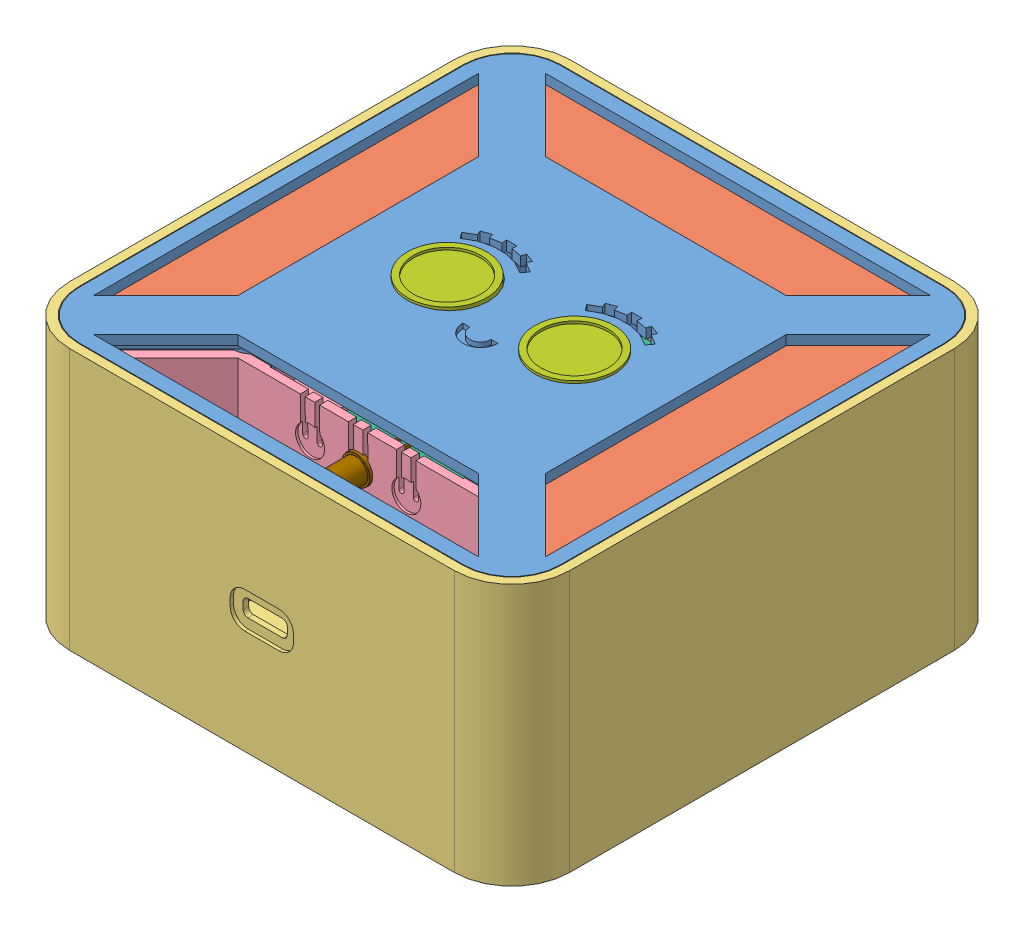
SolidWorks assembly SensorAparcacoches, configuration Default. Lengths in mm.
Overall size (104 54.84 104).
15 component instances, 10 part files, 44 mates.
Components (placement in the parent):
- PlacaFrontal-1: PlacaFrontal [Default] at (-104.2944 -40.3646 79.7073) size (100 19 100)
- Difusor-1: Difusor [Default] at (-104.2944 -40.3646 79.7073) x (-1 0 0) z (0 -1 0) size (84 19 1)
- Difusor-2: Difusor [Default] at (-104.2944 -41.3646 -20.2927) x (-1 0 0) z (0 1 0) size (84 19 1) (hidden)
- Difusor-3: Difusor [Default] at (-104.2944 -41.3646 79.7073) x (0 0 1) z (0 1 0) size (84 19 1)
- Difusor-4: Difusor [Default] at (-4.2944 -41.3646 -20.2927) x (0 0 -1) z (0 1 0) size (84 19 1)
- Cuerpo-2: Cuerpo [Default] at (-4.2944 -54.7045 -20.2927) x (1 0 0) z (0 -1 0) size (104 104 54.34)
- CuadroCentral-1: CuadroCentral [Default] at (-104.2944 -57.3646 79.7073) x (-1 0 0) z (0 -1 0) size (97.8 97.8 18.8)
- Separador-1: Separador [Default] at (-104.2944 -61.3646 79.7073) x (-1 0 0) z (0 -1 0) size (7.47 7.39 15)
- PCB-1: PCB [Default] at (-104.2944 -57.3646 59.978) x (-1 0 0) z (0 0 -1) size (40.2 1.73 60)
- Separador-2: Separador [Default] at (65.7331 -61.3646 -20.2883) x (1 0 0) z (0 -1 0) size (7.47 7.39 15)
- Separador-3: Separador [Default] at (-4.4768 -61.3646 -20.3368) x (1 0 0) z (0 -1 0) size (7.47 7.39 15)
- Ultrassonic sensor HC-SR04-1: Ultrassonic sensor HC-SR04 [Valor predeterminado] at (-77.0515 -50.8646 39.6819) x (1 0 0.000711) z (0 1 0) size (45 23.45 17)
- Arduino-UNO-1: Arduino-UNO [Default] at (-63.9444 -86.5045 52.2561) x (0 0 1) z (-1 0 0) size (53.5 14.9 75.11)
- LED D5 - Red-1: LED D5 - Red [Default] at (-54.2349 -49.9643 61.2596) x (0.98812 0.153685 0) z (0 0 1) size (5.54 5.91 35)
- Altavoz-1: Altavoz [Predeterminado] at (-52.8229 -58.4343 12.7922) size (11.85 15.9 11.85)
Mates (geometry in assembly coordinates):
- InPlace1: in place: plane of ? through (-47.3914 4.3714 47.3521) normal (0 -1 0); plane of ? through (0 4.3714 0) normal (0 -1 0); moOrthogonalPlaneRef_w of ? through (-47.3914 4.3714 47.3521) normal (0 -1 0); plane of ? through (0 4.3714 0) normal (0 0 -1); plane of ? through (-47.3914 4.3714 47.3521) normal (0 -1 0); plane of ? through (0 4.3714 0) normal (-1 0 0); plane of PlacaFrontal-1 through (-104.2944 -40.3646 79.7073) normal (0 -1 0); unknown of ?
- Coincident1: coincident aligned: plane of PlacaFrontal-1; plane of ?
- Coincident2: coincident aligned: moOrthogonalPlaneRef_w of PlacaFrontal-1 through (-104.2944 -40.3646 79.7073) normal (0 0 -1); plane of Part2^SensorAparcacoches-1 through (-47.3914 4.3714 47.3521) normal (0 0 -1)
- Coincident3: coincident anti-aligned: moOrthogonalPlaneRef_w of PlacaFrontal-1 through (-104.2944 -40.3646 79.7073) normal (1 0 0); plane of Part2^SensorAparcacoches-1 through (-47.3914 4.3714 47.3521) normal (-1 0 0)
- InPlace2: in place: plane of ? through (-47.3914 4.3714 47.3521) normal (0 -1 0); plane of ? through (0 4.3714 0) normal (0 -1 0); plane of ? through (-47.3914 4.3714 47.3521) normal (0 -1 0); plane of ? through (0 4.3714 0) normal (0 0 -1); plane of ? through (-47.3914 4.3714 47.3521) normal (0 -1 0); plane of ? through (0 4.3714 0) normal (-1 0 0); plane of PlacaFrontal-1 through (-104.2944 -40.3646 79.7073) normal (0 -1 0); unknown of Difusor-1
- Coincident5: coincident aligned: plane of PlacaFrontal-1; plane of Difusor-1
- Coincident6: coincident aligned: moOrthogonalPlaneRef_w of PlacaFrontal-1 through (-104.2944 -40.3646 79.7073) normal (0 0 -1); plane of Difusor-1 through (-104.2944 -40.3646 79.7073) normal (0 0 -1)
- Coincident7: coincident anti-aligned: moOrthogonalPlaneRef_w of PlacaFrontal-1 through (-104.2944 -40.3646 79.7073) normal (1 0 0); plane of Difusor-1 through (-104.2944 -40.3646 79.7073) normal (-1 0 0)
- Coincident8: coincident anti-aligned: plane of PlacaFrontal-1 through (-104.2944 -40.3646 79.7073) normal (0 -1 0); plane of Difusor-4 through (-101.2944 -40.3646 -10.2927) normal (0 1 0)
- Coincident9: coincident anti-aligned: plane of PlacaFrontal-1 through (-84.2944 -42.3646 79.7073) normal (-1 0 0); plane of Difusor-4 through (-84.2944 -40.3646 54.3476) normal (1 0 0)
- Coincident10: coincident anti-aligned: plane of PlacaFrontal-1 through (-56.3802 -42.3646 31.7931) normal (-0.707107 0 0.707107); plane of Difusor-4 through (-85.2452 -40.3646 2.9281) normal (0.707107 0 -0.707107)
- Coincident11: coincident anti-aligned: plane of PlacaFrontal-1 through (-24.2944 -42.3646 79.7073) normal (1 0 0); plane of Difusor-3 through (-24.2944 -40.3646 5.067) normal (-1 0 0)
- Coincident12: coincident anti-aligned: plane of PlacaFrontal-1 through (-104.2944 -40.3646 79.7073) normal (0 -1 0); plane of Difusor-3 through (-7.2944 -40.3646 69.7073) normal (0 1 0)
- Coincident13: coincident anti-aligned: plane of PlacaFrontal-1 through (-52.2086 -42.3646 27.6215) normal (0.707107 0 -0.707107); plane of Difusor-3 through (-23.3436 -40.3646 56.4865) normal (-0.707107 0 0.707107)
- Coincident14: coincident anti-aligned: plane of PlacaFrontal-1 through (-104.2944 -40.3646 79.7073) normal (0 -1 0); plane of Difusor-2 through (-94.2944 -40.3646 76.7073) normal (0 1 0)
- Coincident15: coincident anti-aligned: plane of PlacaFrontal-1 through (-104.2944 -42.3646 59.7073) normal (0 0 1); plane of Difusor-2 through (-29.6541 -40.3646 59.7073) normal (0 0 -1)
- Coincident16: coincident anti-aligned: plane of PlacaFrontal-1 through (-56.3802 -42.3646 31.7931) normal (-0.707107 0 0.707107); plane of Difusor-2 through (-12.8802 -40.3646 75.2931) normal (0.707107 0 -0.707107)
- Coincident19: coincident anti-aligned: plane of arduino-1 through (-64.9444 -86.5045 52.1061) normal (0 -1 0); plane of Cuerpo-2 through (-96.9444 -86.5045 60.4073) normal (0 1 0)
- Concentric1: concentric anti-aligned: cylinder of arduino-1 through (-46.4444 -86.5045 27.6061) axis (0 1 0) radius 1.5; cylinder of Cuerpo-2 through (-44.9444 -86.5045 28.0061) axis (0 -1 0) radius 1.5
- Parallel1: parallel aligned: plane of arduino-1 through (-97.4444 -85.0045 78.6061) normal (0 0 1); plane of Cuerpo-2 through (-4.2944 108.7136 81.7073) normal (0 0 1)
- Parallel2: parallel anti-aligned: plane of PlacaFrontal-1 through (-104.2944 -40.3646 79.7073) normal (0 -1 0); plane of Cuerpo-2 through (-14.2944 -89.7045 -10.2927) normal (0 1 0)
- Concentric2: concentric aligned: cylinder of PlacaFrontal-1 through (-14.2944 -38.3646 -10.2927) axis (0 -1 0) radius 10; cylinder of Cuerpo-2 through (-14.2944 108.7136 -10.2927) axis (0 -1 0) radius 10.15
- Concentric3: concentric aligned: cylinder of PlacaFrontal-1 through (-94.2944 -38.3646 69.7073) axis (0 -1 0) radius 10; cylinder of Cuerpo-2 through (-94.2944 108.7136 69.7073) axis (0 -1 0) radius 10.15
- InPlace3: in place: plane of PlacaFrontal-1 through (-81.2944 -57.3646 56.7073) normal (0 -1 0); plane of ? through (0 -57.3646 0) normal (0 -1 0); plane of PlacaFrontal-1 through (-81.2944 -57.3646 56.7073) normal (0 -1 0); plane of ? through (0 -57.3646 0) normal (0 0 -1); plane of PlacaFrontal-1 through (-81.2944 -57.3646 56.7073) normal (0 -1 0); plane of ? through (0 -57.3646 0) normal (-1 0 0); plane of PlacaFrontal-1 through (-81.2944 -57.3646 56.7073) normal (0 -1 0); unknown of CuadroCentral-1
- Coincident23: coincident aligned: plane of PlacaFrontal-1; plane of CuadroCentral-1
- Coincident24: coincident aligned: moOrthogonalPlaneRef_w of PlacaFrontal-1 through (-104.2944 -57.3646 79.7073) normal (0 0 -1); plane of CuadroCentral-1 through (-104.2944 -57.3646 79.7073) normal (0 0 -1)
- Coincident25: coincident anti-aligned: moOrthogonalPlaneRef_w of PlacaFrontal-1 through (-104.2944 -57.3646 79.7073) normal (1 0 0); plane of CuadroCentral-1 through (-104.2944 -57.3646 79.7073) normal (-1 0 0)
- InPlace4: in place: plane of CuadroCentral-1 through (-104.2944 -61.3646 79.7073) normal (0 -1 0); plane of ? through (0 -61.3646 0) normal (0 -1 0); plane of CuadroCentral-1 through (-104.2944 -61.3646 79.7073) normal (0 -1 0); plane of ? through (0 -61.3646 0) normal (0 0 -1); plane of CuadroCentral-1 through (-104.2944 -61.3646 79.7073) normal (0 -1 0); plane of ? through (0 -61.3646 0) normal (-1 0 0); plane of CuadroCentral-1 through (-104.2944 -61.3646 79.7073) normal (0 -1 0); unknown of Separador-1
- Coincident20: coincident aligned: plane of CuadroCentral-1; plane of Separador-1
- Coincident21: coincident aligned: moOrthogonalPlaneRef_w of CuadroCentral-1 through (-104.2944 -61.3646 79.7073) normal (0 0 -1); plane of Part5^SensorAparcacoches-1 through (-104.2944 -61.3646 79.7073) normal (0 0 -1)
- Coincident22: coincident anti-aligned: moOrthogonalPlaneRef_w of CuadroCentral-1 through (-104.2944 -61.3646 79.7073) normal (1 0 0); plane of Part5^SensorAparcacoches-1 through (-104.2944 -61.3646 79.7073) normal (-1 0 0)
- InPlace5: in place: plane of CuadroCentral-1 through (-104.2944 -35.5646 59.878) normal (0 0 -1); plane of ? through (0 0 59.878) normal (0 0 -1); plane of CuadroCentral-1 through (-104.2944 -35.5646 59.878) normal (0 0 -1); plane of ? through (0 0 59.878) normal (0 1 0); plane of CuadroCentral-1 through (-104.2944 -35.5646 59.878) normal (0 0 -1); plane of ? through (0 0 59.878) normal (-1 0 0); plane of CuadroCentral-1 through (-104.2944 -35.5646 59.978) normal (0 0 -1); unknown of PCB-1
- Coincident23: coincident aligned: plane of CuadroCentral-1; plane of PCB-1
- Coincident24: coincident aligned: moOrthogonalPlaneRef_w of CuadroCentral-1 through (-104.2944 -57.3646 59.978) normal (0 1 0); plane of PCB-1 through (-104.2944 -57.3646 59.978) normal (0 1 0)
- Coincident25: coincident anti-aligned: moOrthogonalPlaneRef_w of CuadroCentral-1 through (-104.2944 -57.3646 59.978) normal (1 0 0); plane of PCB-1 through (-104.2944 -57.3646 59.978) normal (-1 0 0)
- Coincident26: coincident anti-aligned: plane of CuadroCentral-1 through (-104.2944 -61.3646 79.7073) normal (0 -1 0); plane of Separador-2 through (65.7331 -61.3646 -20.2883) normal (0 1 0)
- Coincident28: coincident anti-aligned: plane of CuadroCentral-1 through (-104.2944 -61.3646 79.7073) normal (0 -1 0); plane of Separador-3 through (-4.4768 -61.3646 -20.3368) normal (0 1 0)
- Concentric7: concentric aligned: cylinder of PlacaFrontal-1 through (-41.2944 -38.3646 29.7073) axis (0 -1 0) radius 8.1; cylinder of Ultrassonic sensor HC-SR04-1 through (-41.2944 -37.8646 29.7073) axis (0 -1 0) radius 8.25
- Coincident30: coincident aligned: plane of PlacaFrontal-1 through (-104.2944 -38.3646 79.7073) normal (0 1 0); plane of Ultrassonic sensor HC-SR04-1 through (-41.2944 -38.3646 29.7073) normal (0 1 0)
- Concentric8: concentric anti-aligned: cylinder of Cuerpo-2 through (-96.9444 -86.5045 33.1061) axis (0 -1 0) radius 1.5; cylinder of Arduino-UNO-1 through (-96.9444 -86.5045 33.1061) axis (0 1 0) radius 1.75
- Coincident31: coincident aligned: plane of Cuerpo-2 through (-96.9444 -86.5045 33.1061) normal (0 1 0); plane of Arduino-UNO-1 through (-63.9444 -86.5045 52.2561) normal (0 1 0)
- Parallel3: parallel aligned: plane of Cuerpo-2 through (-4.2944 108.7136 79.8573) normal (0 0 -1); plane of Arduino-UNO-1 through (-96.9444 -86.5045 79.0061) normal (0 0 -1)
- Concentric9: concentric anti-aligned: cylinder of CuadroCentral-1 through (-54.2349 -49.9643 61.2073) axis (0 0 1) radius 3; cylinder of LED D5 - Red-1 through (-54.2349 -49.9643 62.2096) axis (0 0 -1) radius 2.95
- Coincident32: coincident anti-aligned: plane of PCB-1 through (-34.1237 -58.4343 -0.022) normal (0 1 0); plane of Altavoz-1 through (-52.8229 -58.4343 12.7922) normal (0 -1 0)
